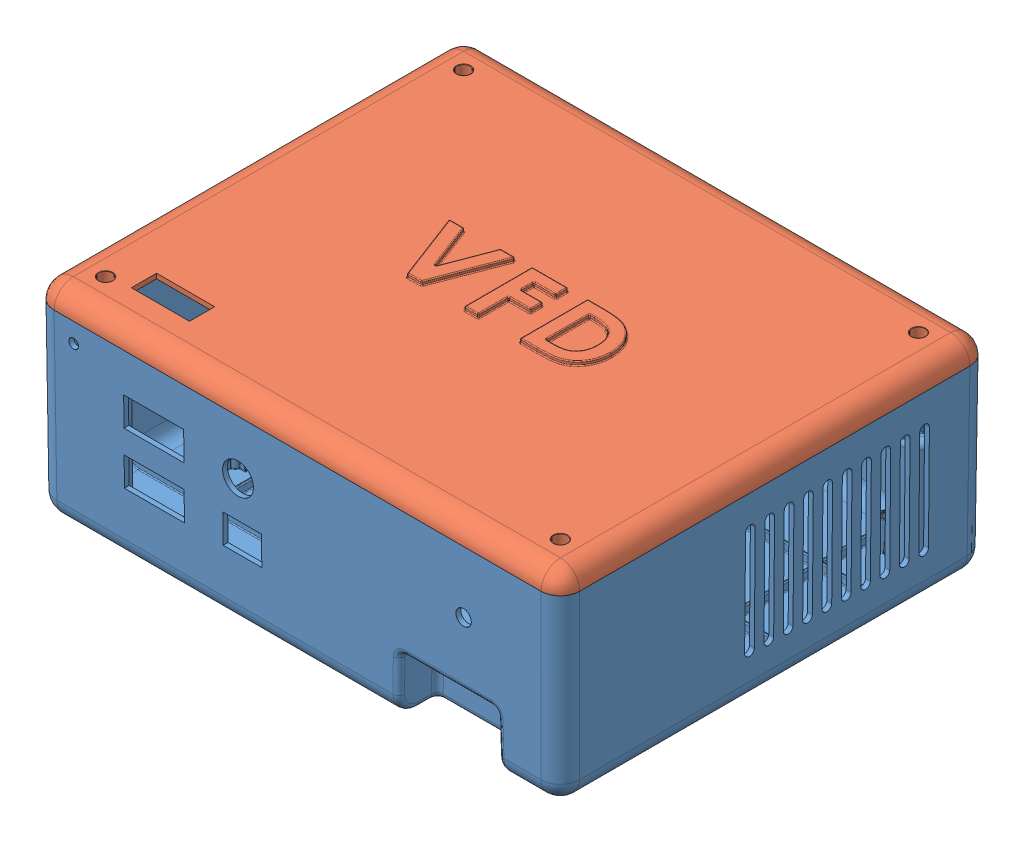
SolidWorks assembly Assembly VFD, configuration Default. Lengths in mm.
Overall size (271.71 108.35 221.71).
2 component instances, 2 part files, 4 mates.
Components (placement in the parent):
- Main-1: Main [Default] at (106.3524 66.3353 200.0861) size (271.66 95.01 221.66)
- Top cover VFD-1: Top cover VFD [Default] at (106.3524 161.3353 200.0861) x (1 0 0) z (0 1 0) size (271.71 221.71 15.35)
Mates (geometry in assembly coordinates):
- InPlace1: in place: plane of Main-1 through (106.3524 156.3353 200.0861) normal (0 1 0); plane of ? through (0 156.3353 0) normal (0 1 0); moOrthogonalPlaneRef_w of Main-1 through (106.3524 156.3353 200.0861) normal (0 1 0); plane of ? through (0 156.3353 0) normal (0 0 -1); plane of Main-1 through (106.3524 156.3353 200.0861) normal (0 1 0); plane of ? through (0 156.3353 0) normal (1 0 0); plane of Main-1 through (106.3524 161.3353 200.0861) normal (0 1 0); unknown of Top cover VFD-1
- Coincident1: coincident aligned: plane of Main-1; plane of Top cover VFD-1
- Coincident2: coincident aligned: moOrthogonalPlaneRef_w of Main-1 through (106.3524 161.3353 200.0861) normal (0 0 -1); plane of Top cover VFD-1 through (106.3524 161.3353 200.0861) normal (0 0 -1)
- Coincident3: coincident anti-aligned: moOrthogonalPlaneRef_w of Main-1 through (106.3524 161.3353 200.0861) normal (-1 0 0); plane of Top cover VFD-1 through (106.3524 161.3353 200.0861) normal (1 0 0)
